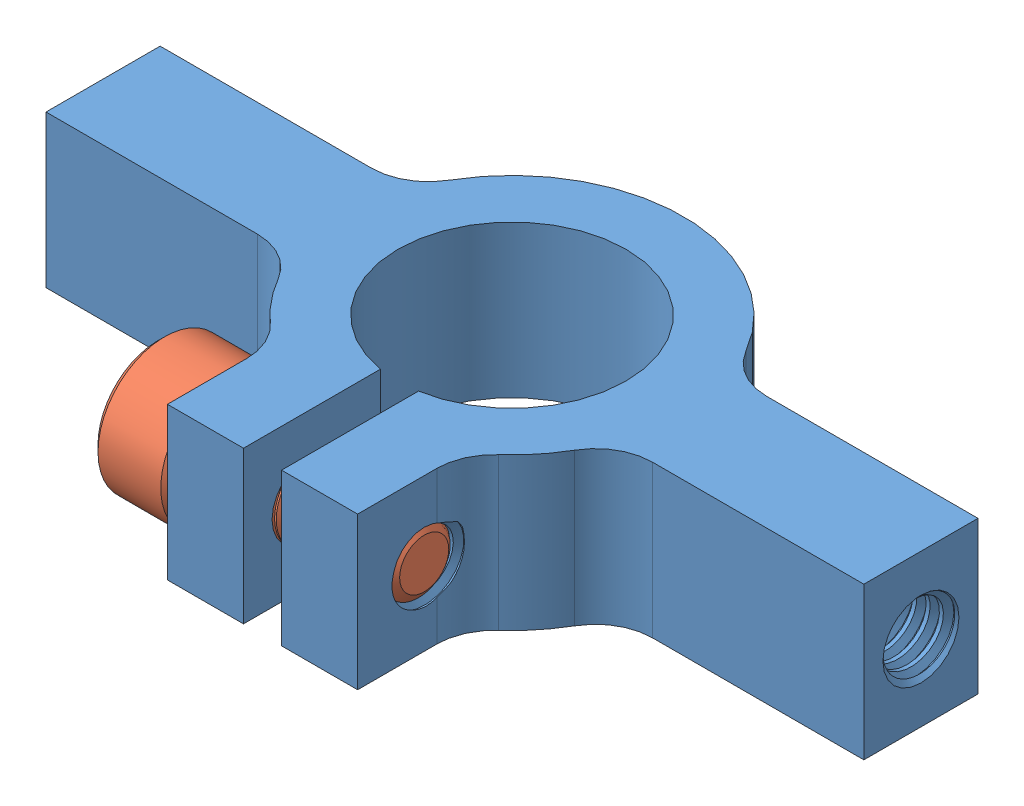
SolidWorks assembly 2-Side, 1-Post Clamping Mount (43mm Width, 12mm Bore) 1402-0043-0012, configuration Default. Lengths in mm.
Overall size (43.01 8 22.12).
2 component instances, 2 part files, 0 mates.
Components (placement in the parent):
- 1402-0043-0012.step-1: 1402-0043-0012.step [Default] at (0.005 3.9969 -2.0671) size (43.01 8 22.12)
- 2800-0004-0010.step-1: 2800-0004-0010.step [Default] at (5.005 -0.0031 7.549) x (0 0 1) z (0 -1 0) size (7 14.01 7)
